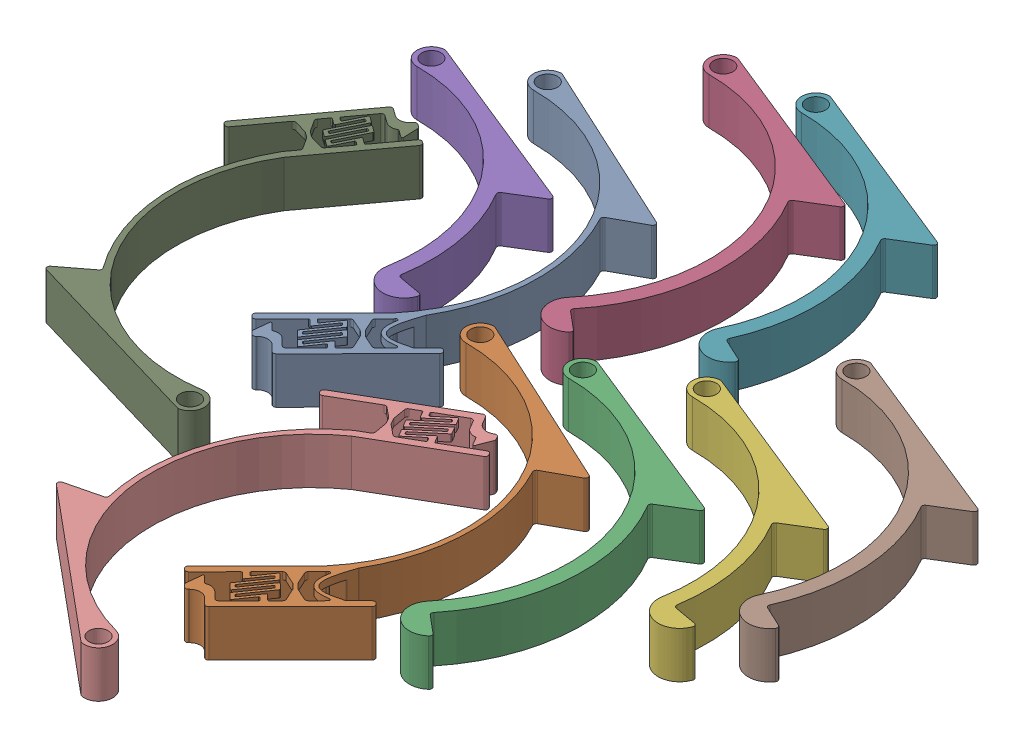
SolidWorks assembly ArmBandforPrinting v5, configuration Default. Lengths in mm.
Overall size (204.05 13 238.88).
10 component instances, 5 part files, 9 mates.
Components (placement in the parent):
- Arm Clamp v3.2-1: Arm Clamp v3.2 [Default] at (-17.8261 -0.3208 9.6245) size (55.12 13 108.47)
- Arm Clamp v3.2-2: Arm Clamp v3.2 [Default] at (34.1907 -0.3208 80.5649) size (55.12 13 108.47)
- Arm Clamp - long v6-1: Arm Clamp - long v6 [Default] at (57.1634 -0.3208 74.7416) size (54.95 13 91.78)
- Arm Clamp - long v6-2: Arm Clamp - long v6 [Default] at (3.0062 -0.3208 -18.8242) size (54.95 13 91.78)
- Arm Clamp - short v6-1: Arm Clamp - short v6 [Default] at (-39.881 -0.3208 20.2363) size (59.95 13 67.85)
- Arm Clamp - short v6-2: Arm Clamp - short v6 [Default] at (79.1108 -0.3208 61.9003) size (59.95 13 67.85)
- Arm Clamp - medium v6-1: Arm Clamp - medium v6 [Default] at (25.3294 -0.3208 -22.5068) size (55.34 13 80.55)
- Arm Clamp - medium v6-2: Arm Clamp - medium v6 [Default] at (95.8072 -0.3208 36.6164) size (55.34 13 80.55)
- Arm Clamp v3.3-1: Arm Clamp v3.3 [Default] at (1.8468 -0.3208 39.5185) x (-0.989016 0 0.147809) z (-0.147809 0 -0.989016) size (55.12 13 108.47)
- Arm Clamp v3.3-2: Arm Clamp v3.3 [Default] at (66.5836 -0.3208 111.1425) x (-0.965926 0 -0.258819) z (0.258819 0 -0.965926) size (55.12 13 108.47)
Mates (geometry in assembly coordinates):
- Coincident1: coincident aligned: plane of Arm Clamp v3.2-1 through (-17.8261 -0.3208 9.6245) normal (0 -1 0); plane of Arm Clamp v3.2-2 through (34.1907 -0.3208 80.5649) normal (0 -1 0)
- Coincident2: coincident aligned: plane of Arm Clamp v3.2-1 through (-17.8261 -0.3208 9.6245) normal (0 -1 0); plane of Arm Clamp - long v6-1 through (57.1634 -0.3208 74.7416) normal (0 -1 0)
- Coincident3: coincident aligned: plane of Arm Clamp v3.2-1 through (-17.8261 -0.3208 9.6245) normal (0 -1 0); plane of Arm Clamp - medium v6-1 through (25.3294 -0.3208 -22.5068) normal (0 -1 0)
- Coincident4: coincident aligned: plane of Arm Clamp v3.2-1 through (-17.8261 -0.3208 9.6245) normal (0 -1 0); plane of Arm Clamp - long v6-2 through (3.0062 -0.3208 -18.8242) normal (0 -1 0)
- Coincident5: coincident aligned: plane of Arm Clamp v3.2-1 through (-17.8261 -0.3208 9.6245) normal (0 -1 0); plane of Arm Clamp - medium v6-2 through (95.8072 -0.3208 36.6164) normal (0 -1 0)
- Coincident6: coincident aligned: plane of Arm Clamp v3.2-1 through (-17.8261 -0.3208 9.6245) normal (0 -1 0); plane of Arm Clamp - short v6-1 through (-39.881 -0.3208 20.2363) normal (0 -1 0)
- Coincident7: coincident aligned: plane of Arm Clamp v3.2-1 through (-17.8261 -0.3208 9.6245) normal (0 -1 0); plane of Arm Clamp - short v6-2 through (79.1108 -0.3208 61.9003) normal (0 -1 0)
- Coincident8: coincident aligned: plane of Arm Clamp v3.2-1 through (-17.8261 -0.3208 9.6245) normal (0 -1 0); plane of Arm Clamp v3.3-1 through (1.8468 -0.3208 39.5185) normal (0 -1 0)
- Coincident9: coincident aligned: plane of Arm Clamp v3.2-2 through (34.1907 -0.3208 80.5649) normal (0 -1 0); plane of Arm Clamp v3.3-2 through (66.5836 -0.3208 111.1425) normal (0 -1 0)
